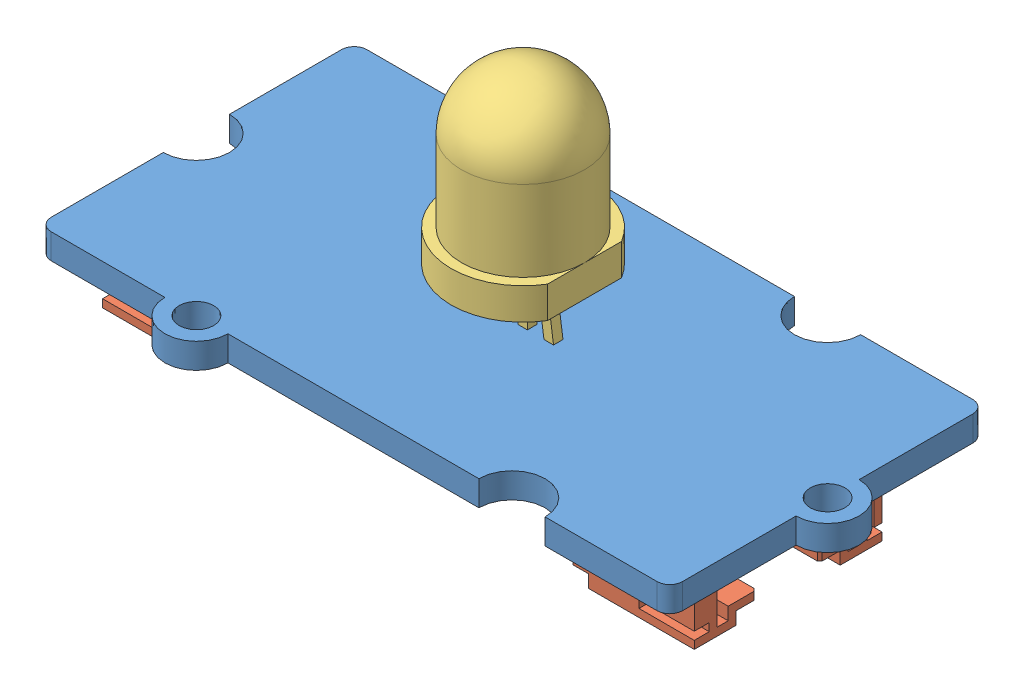
SolidWorks assembly Grove Chainable RGB LED v2.0, configuration Défaut. Lengths in mm.
Overall size (42 20.8 24).
11 component instances, 6 part files, 13 mates.
Components (placement in the parent):
- PCB Grove 20x40 Special - Chainable RGB Led v2.0-1: PCB Grove 20x40 Special - Chainable RGB Led v2.0 [Défaut] at (4.6979 1.1208 42) size (42 6.6 24)
  - PCB Grove 20x40 - Chainable RGB Led v2.0-1: PCB Grove 20x40 - Chainable RGB Led v2.0 [Défaut] at (-6.8616 2.7799 42) size (42 1.6 24)
  - Connector Grove SMD Horizontal-1: Connector Grove SMD Horizontal [Défaut] at (2.9384 -3.0201 42) x (0 0 -1) z (0 -1 0) size (12.95 10.75 5)
  - Connector Grove SMD Horizontal-2: Connector Grove SMD Horizontal [Défaut] at (-19.1616 -3.0201 42) x (0 0 1) z (0 -1 0) size (12.95 10.75 5)
- RGB LED-1: RGB LED [Défaut] at (-1.4637 9.9007 84) x (0 0 -1) z (1 0 0) size (9.1 15.95 8.45)
- Capacitor 603-1: Capacitor 603 [Default] at (1.2627 3.1007 77.63) x (-1 0 0) z (0 0 1) size (2.76 0.9 1.12)
- Capacitor 603-2: Capacitor 603 [Default] at (-0.7937 3.1007 87.9993) x (0 0 -1) z (-1 0 0) size (2.76 0.9 1.12)
- Resistor 390-1: Resistor 390 [Default] at (-2.8237 3.1007 87.9993) x (0 0 -1) z (-1 0 0) size (2.36 0.62 1.03)
- Resistor 390-2: Resistor 390 [Default] at (-4.7237 3.1007 87.9993) x (0 0 -1) z (-1 0 0) size (2.36 0.62 1.03)
- Resistor-3: Resistor [Default] at (1.2627 3.1007 79.41) x (-1 0 0) z (0 0 1) size (2.36 0.6 1.03)
- Resistor-4: Resistor [Default] at (1.2627 3.1007 81.16) x (-1 0 0) z (0 0 1) size (2.36 0.6 1.03)
Mates (geometry in assembly coordinates):
- Distance3: distance = 0.1 mm aligned: plane of PCB Grove 20x40 Special - Chainable RGB Led v2.0-1/PCB Grove 20x40 - Chainable RGB Led v2.0-1 through (-2.1637 3.1007 84) normal (0 -1 0); plane of RGB LED-1 through (-1.4637 3.0007 84) normal (0 -1 0)
- Coïncidente3: coincident anti-aligned: plane of PCB Grove 20x40 Special - Chainable RGB Led v2.0-1/PCB Grove 20x40 - Chainable RGB Led v2.0-1 through (-2.1637 3.9007 84) normal (0 0 1); plane of RGB LED-1 through (-1.4637 9.9007 84) normal (0 0 -1)
- Distance2: distance = 4.6 mm aligned: plane of RGB LED-1 through (2.4363 7.9007 81.6564) normal (1 0 0); plane of PCB Grove 20x40 Special - Chainable RGB Led v2.0-1/PCB Grove 20x40 - Chainable RGB Led v2.0-1 through (-2.1637 3.9007 84) normal (1 0 0)
- Coïncidente6: coincident anti-aligned: plane of PCB Grove 20x40 Special - Chainable RGB Led v2.0-1/PCB Grove 20x40 - Chainable RGB Led v2.0-1 through (-2.1637 3.1007 84) normal (0 -1 0); plane of Capacitor 603-1 through (1.2627 3.1007 77.63) normal (0 1 0)
- Coïncidente7: coincident anti-aligned: plane of PCB Grove 20x40 Special - Chainable RGB Led v2.0-1/PCB Grove 20x40 - Chainable RGB Led v2.0-1 through (-2.1637 3.1007 84) normal (0 -1 0); plane of Capacitor 603-2 through (-0.7937 3.1007 87.9993) normal (0 1 0)
- Distance4: distance = 3.25 mm aligned: plane of Capacitor 603-1 through (0.8627 2.9757 77.25) normal (0 0 -1); plane of PCB Grove 20x40 Special - Chainable RGB Led v2.0-1/PCB Grove 20x40 - Chainable RGB Led v2.0-1 through (-2.1637 4.7007 74) normal (0 0 -1)
- Distance5: distance = 18.25 mm aligned: plane of Capacitor 603-2 through (-0.4137 2.9757 87.5993) normal (1 0 0); plane of PCB Grove 20x40 Special - Chainable RGB Led v2.0-1/PCB Grove 20x40 - Chainable RGB Led v2.0-1 through (17.8363 4.7007 84) normal (1 0 0)
- Coïncidente10: coincident anti-aligned: plane of PCB Grove 20x40 Special - Chainable RGB Led v2.0-1/PCB Grove 20x40 - Chainable RGB Led v2.0-1 through (-2.1637 3.1007 84) normal (0 -1 0); plane of Resistor 390-1 through (-2.8237 3.1007 87.9993) normal (0 1 0)
- Distance6: distance = 1.25 mm anti-aligned: plane of Resistor 390-1 through (-2.4237 2.5257 87.2243) normal (1 0 0); plane of Capacitor 603-2 through (-1.1737 2.9757 87.5993) normal (-1 0 0)
- Coïncidente12: coincident aligned: plane of Capacitor 603-2 through (-0.7937 3.1007 87.9993) normal (0 0 -1); plane of Resistor 390-1 through (-2.8237 3.1007 87.9993) normal (0 0 -1)
- Coïncidente13: coincident anti-aligned: plane of PCB Grove 20x40 Special - Chainable RGB Led v2.0-1/PCB Grove 20x40 - Chainable RGB Led v2.0-1 through (-2.1637 3.1007 84) normal (0 -1 0); plane of Resistor-3 through (1.2627 3.1007 79.41) normal (0 1 0)
- Distance7: distance = 1 mm anti-aligned: plane of Resistor-3 through (0.4877 2.5257 79.01) normal (0 0 -1); plane of Capacitor 603-1 through (0.8627 2.9757 78.01) normal (0 0 1)
- Coïncidente15: coincident aligned: plane of Capacitor 603-1 through (1.2627 3.1007 77.63) normal (-1 0 0); plane of Resistor-3 through (1.2627 3.1007 79.41) normal (-1 0 0)
